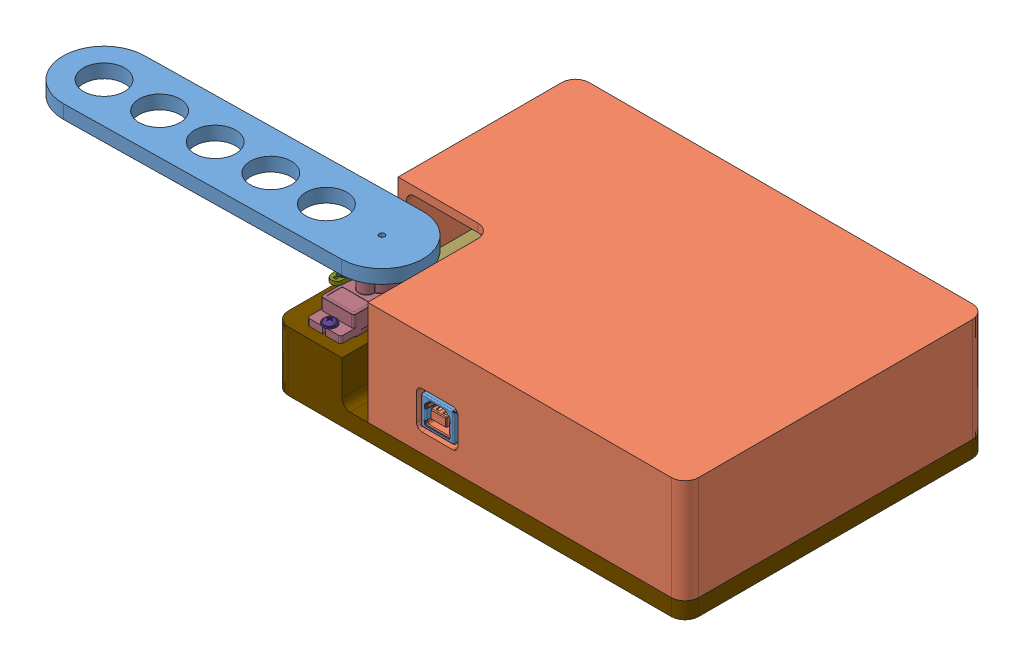
SolidWorks assembly mounted_assem, configuration Default. Lengths in mm.
Overall size (251.12 44 110).
146 component instances, 56 part files, 53 mates.
Components (placement in the parent):
- arduino uno-1: arduino uno [Default] at (97.5 14.03 -6.35) size (53.34 15.25 74.93)
  - USB type b-1: USB type b [Default] at (-38.02 0.43 6.35) size (13.72 15.2 16.5)
    - USB SHELL-1: USB SHELL [Default] at origin size (13.72 15.2 16.5)
    - USB core-1: USB core [Default] at origin size (11.3 10.68 15.75)
    - usb top contact-1: usb top contact [Default] at (1.25 6.09 -0.38) size (1 9.67 13.76)
    - usb top contact-2: usb top contact [Default] at (-1.25 6.09 -0.38) size (1 9.67 13.76)
    - usb btm contact-1: usb btm contact [Default] at (1.25 4.41 -0.38) size (1 6.84 11.76)
    - usb btm contact-2: usb btm contact [Default] at (-1.25 4.41 -0.38) size (1 6.84 11.76)
  - dip28-1: dip28 [Default] at (-16.383 1.5 -46.355) x (0 0 -1) z (1 0 0) size (35.48 7.37 10.1)
    - dip28-1: dip28 [Default] at origin size (35.48 2.8 10.1)
    - dip socket pin-1: dip socket pin [Default] at (-6.35 2.8 -3.81) size (1.7 7.37 1.7)
    - dip socket pin-2: dip socket pin [Default] at (1.27 2.8 -3.81) size (1.7 7.37 1.7)
    - dip socket pin-3: dip socket pin [Default] at (-16.51 2.8 3.81) size (1.7 7.37 1.7)
    - dip socket pin-4: dip socket pin [Default] at (1.27 2.8 3.81) size (1.7 7.37 1.7)
    - dip socket pin-5: dip socket pin [Default] at (6.35 2.8 -3.81) size (1.7 7.37 1.7)
    - dip socket pin-6: dip socket pin [Default] at (13.97 2.8 -3.81) size (1.7 7.37 1.7)
    - dip socket pin-7: dip socket pin [Default] at (3.81 2.8 -3.81) size (1.7 7.37 1.7)
    - dip socket pin-8: dip socket pin [Default] at (-13.97 2.8 3.81) size (1.7 7.37 1.7)
    - dip socket pin-9: dip socket pin [Default] at (16.51 2.8 3.81) size (1.7 7.37 1.7)
    - dip socket pin-10: dip socket pin [Default] at (13.97 2.8 3.81) size (1.7 7.37 1.7)
    - dip socket pin-11: dip socket pin [Default] at (-1.27 2.8 3.81) size (1.7 7.37 1.7)
    - dip socket pin-12: dip socket pin [Default] at (-11.43 2.8 -3.81) size (1.7 7.37 1.7)
    - dip socket pin-13: dip socket pin [Default] at (11.43 2.8 3.81) size (1.7 7.37 1.7)
    - dip socket pin-14: dip socket pin [Default] at (-8.89 2.8 -3.81) size (1.7 7.37 1.7)
    - dip socket pin-15: dip socket pin [Default] at (-1.27 2.8 -3.81) size (1.7 7.37 1.7)
    - dip socket pin-16: dip socket pin [Default] at (16.51 2.8 -3.81) size (1.7 7.37 1.7)
    - dip socket pin-17: dip socket pin [Default] at (-13.97 2.8 -3.81) size (1.7 7.37 1.7)
    - dip socket pin-18: dip socket pin [Default] at (-3.81 2.8 3.81) size (1.7 7.37 1.7)
    - dip socket pin-19: dip socket pin [Default] at (8.89 2.8 -3.81) size (1.7 7.37 1.7)
    - dip socket pin-20: dip socket pin [Default] at (-6.35 2.8 3.81) size (1.7 7.37 1.7)
    - dip socket pin-21: dip socket pin [Default] at (3.81 2.8 3.81) size (1.7 7.37 1.7)
    - dip socket pin-22: dip socket pin [Default] at (11.43 2.8 -3.81) size (1.7 7.37 1.7)
    - dip socket pin-23: dip socket pin [Default] at (8.89 2.8 3.81) size (1.7 7.37 1.7)
    - dip socket pin-24: dip socket pin [Default] at (-16.51 2.8 -3.81) size (1.7 7.37 1.7)
    - dip socket pin-25: dip socket pin [Default] at (-3.81 2.8 -3.81) size (1.7 7.37 1.7)
    - dip socket pin-26: dip socket pin [Default] at (-8.89 2.8 3.81) size (1.7 7.37 1.7)
    - dip socket pin-27: dip socket pin [Default] at (-11.43 2.8 3.81) size (1.7 7.37 1.7)
    - dip socket pin-28: dip socket pin [Default] at (6.35 2.8 3.81) size (1.7 7.37 1.7)
  - RESET BUTTON-1: RESET BUTTON [Default] at (-49.403 0 -6.35) size (6.2 3.1 9.6)
    - RESET CORE-1: RESET CORE [Default] at (0 0.1 0) x (-1 0 0) z (0 0 -1) size (6.2 3.1 9.6)
    - RESET-1: RESET [Default] at (0 0.1 0) x (0 0 1) z (-1 0 0) size (7.3 2 6.2)
  - unoboard blue-1: unoboard blue [Default] at origin size (53.34 1.65 68.58)
  - 47uf CAP Dcase-1: 47uf CAP Dcase [Default] at (-9.4141 0 -25.7132) x (0 0 -1) z (1 0 0) size (6.6 5.81 8)
  - 47uf CAP Dcase-2: 47uf CAP Dcase [Default] at (-9.4141 0 -18.4991) x (0 0 -1) z (1 0 0) size (6.6 5.81 8)
  - power jack-1: power jack [Default] at (-7.675 0 1.905) size (11.2 15.2 15.9)
  - crystal-1: crystal [Default] at (-26.162 0 -18.923) x (1 0 0) z (0 0 -1) size (4 5 11)
  - 2pin_header__02-1: 2pin_header__02 [Default] at (-46.23 0 -20.83) size (5 11.75 2.54)
  - 2pin_header__02-2: 2pin_header__02 [Default] at (-27.89 0 -64.91) x (0 0 1) z (-1 0 0) size (5 11.75 2.54)
  - 2pin_header__02-3: 2pin_header__02 [Default] at (-46.23 0 -15.75) size (5 11.75 2.54)
  - 2pin_header__02-4: 2pin_header__02 [Default] at (-46.23 0 -18.29) size (5 11.75 2.54)
  - 2pin_header__02-5: 2pin_header__02 [Default] at (-25.35 0 -64.91) x (0 0 1) z (-1 0 0) size (5 11.75 2.54)
  - 2pin_header__02-6: 2pin_header__02 [Default] at (-30.43 0 -64.91) x (0 0 1) z (-1 0 0) size (5 11.75 2.54)
  - nano - reg-1: nano - reg [Default] at (-17.399 0 -7.747) size (6.5 1.69 8.3)
  - led-1: led [Default] at (-36.576 0 -58.42) x (0 0 1) z (-1 0 0) size (4 0.86 1.35)
  - led-2: led [Default] at (-34.29 0 -27.94) x (0 0 1) z (-1 0 0) size (4 0.86 1.35)
  - led-3: led [Default] at (-36.83 0 -27.94) x (0 0 1) z (-1 0 0) size (4 0.86 1.35)
  - led-4: led [Default] at (-42.037 0 -27.94) x (0 0 1) z (-1 0 0) size (4 0.86 1.35)
  - atmega16u2-1: atmega16u2 [Default] at (-34.671 0.06 -20) x (1 0 0) z (0 0 -1) size (5.5 1.01 5.5)
  - 8 PORT HEADER-1: 8 PORT HEADER [Default] at (-50.8 0 -45.72) x (0 0 -1) z (1 0 0) size (20.32 10.51 2.41)
  - 8 PORT HEADER-2: 8 PORT HEADER [Default] at (-2.54 0 -27.94) x (0 0 -1) z (1 0 0) size (20.32 10.51 2.41)
  - 6 PORT HEADER-1: 6 PORT HEADER [Default] at (-2.54 0 -50.8) x (0 0 -1) z (1 0 0) size (15.24 10.51 2.41)
  - 10 PORT HEADER-1: 10 PORT HEADER [Default] at (-50.8 0 -18.796) x (0 0 -1) z (1 0 0) size (25.4 10.51 2.41)
  - ATMEL328P-1: ATMEL328P [Default] at (-16.383 4.3 -46.355) x (0 0 -1) z (1 0 0) size (35 7.27 7.87)
  - 102 RESISTOR PACK-1: 102 RESISTOR PACK [Default] at (-39.37 0 -27.94) size (3.2 0.46 3)
  - 102 RESISTOR PACK-2: 102 RESISTOR PACK [Default] at (-33.782 0 -58.42) size (3.2 0.46 3)
  - 103 RESISTOR PACK-1: 103 RESISTOR PACK [Default] at (-23.876 0 -27.94) size (3.2 0.46 3)
  - 220 RESISTOR PACK-1: 220 RESISTOR PACK [Default] at (-36.83 0 -12.827) size (3.2 0.46 3)
  - 16mhz crystal - measured-1: 16mhz crystal - measured [Default] at (-24.892 0 -41.275) x (0 0 -1) z (1 0 0) size (3.4 0.8 2)
  - PADS001-1: PADS001 [Default] at (-39.878 0.1 -18.288) x (-1 0 0) z (0 0 1) size (4.54 0.1 4.54)
  - 603 cap on pad-1: 603 cap on pad [Default] at (-29.591 0 -22.352) x (0 0 1) z (-1 0 0) size (2.76 0.9 1.12)
  - 603 cap on pad-2: 603 cap on pad [Default] at (-29.845 0 -27.94) x (0 0 -1) z (1 0 0) size (2.76 0.9 1.12)
  - 603 cap on pad-3: 603 cap on pad [Default] at (-29.845 0 -12.065) x (0 0 1) z (-1 0 0) size (2.76 0.9 1.12)
  - 603 cap on pad-4: 603 cap on pad [Default] at (-44.45 0 -27.94) x (0 0 -1) z (1 0 0) size (2.76 0.9 1.12)
  - 603 cap on pad-5: 603 cap on pad [Default] at (-41.91 0 -12.7) x (0 0 1) z (-1 0 0) size (2.76 0.9 1.12)
  - 603 cap on pad-6: 603 cap on pad [Default] at (-29.591 0 -16.002) x (0 0 1) z (-1 0 0) size (2.76 0.9 1.12)
  - 603 cap on pad-7: 603 cap on pad [Default] at (-31.496 0 -27.94) x (0 0 -1) z (1 0 0) size (2.76 0.9 1.12)
  - 603 cap on pad-8: 603 cap on pad [Default] at (-15.24 0 -18.415) size (2.76 0.9 1.12)
  - 603 cap on pad-9: 603 cap on pad [Default] at (-15.24 0 -25.625) size (2.76 0.9 1.12)
  - ssot3-1: ssot3 [Default] at (-26.5 0 -8.128) x (-1 0 0) z (0 0 -1) size (3 1.13 3.09)
  - mf-msmf050-2-1: mf-msmf050-2 [Default] at (-26.5 0 -4.064) size (5.77 1.02 3.72)
  - lmv358-1: lmv358 [Default] at (-15.24 0 -21.971) x (0 0 -1) z (1 0 0) size (3.7 1.4 2.9)
  - lp2985dgkr-1: lp2985dgkr [Default] at (-20.32 0 -19.05) x (0 0 -1) z (1 0 0) size (5.85 1.1 3)
  - cd1206 diode-1: cd1206 diode [Default] at (-27.94 0 -59.436) x (0 0 -1) z (1 0 0) size (2.07 0.96 5)
  - cd1206 diode-2: cd1206 diode [Default] at (-46.228 0 -13.081) x (0 0 1) z (-1 0 0) size (2.07 0.96 5)
  - 603 resistor-1: 603 resistor [Default] at (-29.591 0 -19.05) x (0 0 1) z (-1 0 0) size (2.36 0.61 1.03)
  - blm21-1: blm21 [Default] at (-45.085 0 -7.62) x (0 0 -1) z (1 0 0) size (2.76 0.95 1.32)
  - m7 diode-1: m7 diode [Default] at (-2.794 0 -21.59) x (0 0 -1) z (1 0 0) size (6.66 2.35 2.5)
  - MLC0603-1: MLC0603 [Default] at (-33.655 0 -12.827) x (0 0 -1) z (1 0 0) size (2.36 0.6 1.03)
  - MLC0603-2: MLC0603 [Default] at (-39.37 0 -12.827) x (0 0 -1) z (1 0 0) size (2.36 0.6 1.03)
- mounting_plate-1: mounting_plate [FDM] at origin size (150 39 110)
- standoff-1: standoff [6mm] at (89.88 6.38 -72.39) x (0 0 1) z (-1 0 0) size (5.2 6 5.2)
- standoff-2: standoff [6mm] at (61.94 6.38 -72.39) x (0 0 1) z (-1 0 0) size (5.2 6 5.2)
- standoff-3: standoff [6mm] at (94.96 6.38 -20.32) x (0 0 1) z (-1 0 0) size (5.2 6 5.2)
- standoff-4: standoff [6mm] at (46.7 6.38 -21.59) x (0 0 1) z (-1 0 0) size (5.2 6 5.2)
- protoboard-1: protoboard [Default] at (44.16 12.38 -82) size (47.5 3 24)
- RFID.STEP-1: RFID.STEP [Default] at (117.8439 -27.45 -59.2288) x (1 0 0) z (0 1 0) size (40 60 11.55)
  - Part1^RFID.STEP-1: Part1^RFID.STEP [Default] at (-16.3439 30.7712 59.45) size (40 60 2) (virtual)
  - Part10^RFID.STEP-1: Part10^RFID.STEP [Default] at (20.709 20.1029 60.45) x (0 1 0) z (0 0 1) size (10.67 3.05 5.63) (virtual)
  - User Library-S-PWSON-N12^RFID.STEP-1: User Library-S-PWSON-N12^RFID.STEP [Default] at (4.1233 20.047 60.45) x (1 0 0) z (0 -1 0) size (3 0.8 3) (virtual)
  - User Library-Header_Male_8Pin^RFID.STEP-1: User Library-Header_Male_8Pin^RFID.STEP [Default] at (12.9823 28.5305 62.74) x (-1 0 0) z (0 0 -1) size (20.33 2.5 11.55) (virtual)
  - User Library-SMD Ceramic Capacitors_0603 (1608)_CH.STEP-1: User Library-SMD Ceramic Capacitors_0603 (1608)_CH.STEP [Default] at (-3.9959 5.9247 60.9127) size (1.68 0.88 0.93)
  - User Library-SMD Ceramic Capacitors_0603 (1608)_CH.STEP-2: User Library-SMD Ceramic Capacitors_0603 (1608)_CH.STEP [Default] at (-1.0806 5.9034 60.9127) size (1.68 0.88 0.93)
  - User Library-SMD Ceramic Capacitors_0603 (1608)_CH.STEP-3: User Library-SMD Ceramic Capacitors_0603 (1608)_CH.STEP [Default] at (2.2282 5.9089 60.9127) size (1.68 0.88 0.93)
  - User Library-SMD Ceramic Capacitors_0603 (1608)_CH.STEP-4: User Library-SMD Ceramic Capacitors_0603 (1608)_CH.STEP [Default] at (5.214 5.921 60.9127) size (1.68 0.88 0.93)
  - User Library-SMD Ceramic Capacitors_0603 (1608)_CH.STEP-5: User Library-SMD Ceramic Capacitors_0603 (1608)_CH.STEP [Default] at (8.193 5.9188 60.9127) size (1.68 0.88 0.93)
  - User Library-SMD Ceramic Capacitors_0603 (1608)_CH.STEP-6: User Library-SMD Ceramic Capacitors_0603 (1608)_CH.STEP [Default] at (11.3855 5.9271 60.9127) size (1.68 0.88 0.93)
  - User Library-SMD Ceramic Capacitors_0603 (1608)_CH.STEP-7: User Library-SMD Ceramic Capacitors_0603 (1608)_CH.STEP [Default] at (16.3593 23.3789 60.9127) size (1.68 0.88 0.93)
  - User Library-SMD Ceramic Capacitors_0603 (1608)_CH.STEP-8: User Library-SMD Ceramic Capacitors_0603 (1608)_CH.STEP [Default] at (16.3593 21.3117 60.9127) size (1.68 0.88 0.93)
  - User Library-SMD Ceramic Capacitors_0603 (1608)_CH.STEP-9: User Library-SMD Ceramic Capacitors_0603 (1608)_CH.STEP [Default] at (13.4136 25.6528 60.9127) size (1.68 0.88 0.93)
  - User Library-SMD Ceramic Capacitors_0603 (1608)_CH.STEP-10: User Library-SMD Ceramic Capacitors_0603 (1608)_CH.STEP [Default] at (13.517 19.0895 60.9127) size (1.68 0.88 0.93)
  - Part8^RFID.STEP-1: Part8^RFID.STEP [Default] at (13.517 23.4826 60.704) size (1.6 0.81 0.51) (virtual)
  - Part8^RFID.STEP-2: Part8^RFID.STEP [Default] at (13.517 21.3121 60.704) size (1.6 0.81 0.51) (virtual)
  - User Library-SMD Ceramic Capacitors_0603 (1608)_CH.STEP-11: User Library-SMD Ceramic Capacitors_0603 (1608)_CH.STEP [Default] at (-5.0547 25.4542 60.9127) size (1.68 0.88 0.93)
  - User Library-SMD Ceramic Capacitors_0603 (1608)_CH.STEP-12: User Library-SMD Ceramic Capacitors_0603 (1608)_CH.STEP [Default] at (-5.0547 21.4355 60.9127) size (1.68 0.88 0.93)
  - User Library-SMD Ceramic Capacitors_0603 (1608)_CH.STEP-13: User Library-SMD Ceramic Capacitors_0603 (1608)_CH.STEP [Default] at (-5.0547 19.367 60.9127) size (1.68 0.88 0.93)
  - Part8^RFID.STEP-3: Part8^RFID.STEP [Default] at (-5.0547 23.3861 60.704) size (1.6 0.81 0.51) (virtual)
  - Part8^RFID.STEP-4: Part8^RFID.STEP [Default] at (-10.0418 25.4159 60.704) size (1.6 0.81 0.51) (virtual)
  - Part8^RFID.STEP-5: Part8^RFID.STEP [Default] at (-10.0625 23.4569 60.704) size (1.6 0.81 0.51) (virtual)
  - Part8^RFID.STEP-6: Part8^RFID.STEP [Default] at (-10.0541 27.4204 60.704) size (1.6 0.81 0.51) (virtual)
- 94180A331_Tapered Heat-Set Inserts for Plastic-3: 94180A331_Tapered Heat-Set Inserts for Plastic [94180A331] at (49.16 4.48 -99.5) x (1 0 0) z (0 1 0) size (5.56 5.56 3.8)
- 94180A331_Tapered Heat-Set Inserts for Plastic-5: 94180A331_Tapered Heat-Set Inserts for Plastic [94180A331] at (46.7 4.48 -21.59) x (1 0 0) z (0 1 0) size (5.56 5.56 3.8)
- 94180A331_Tapered Heat-Set Inserts for Plastic-7: 94180A331_Tapered Heat-Set Inserts for Plastic [94180A331] at (61.94 4.48 -72.39) x (1 0 0) z (0 1 0) size (5.56 5.56 3.8)
- 94180A331_Tapered Heat-Set Inserts for Plastic-8: 94180A331_Tapered Heat-Set Inserts for Plastic [94180A331] at (89.88 4.48 -72.39) x (1 0 0) z (0 1 0) size (5.56 5.56 3.8)
- 94180A331_Tapered Heat-Set Inserts for Plastic-9: 94180A331_Tapered Heat-Set Inserts for Plastic [94180A331] at (94.96 4.48 -20.32) x (1 0 0) z (0 1 0) size (5.56 5.56 3.8)
- 94180A331_Tapered Heat-Set Inserts for Plastic-10: 94180A331_Tapered Heat-Set Inserts for Plastic [94180A331] at (86.66 4.48 -99.5) x (1 0 0) z (0 1 0) size (5.56 5.56 3.8)
- vl53l0x-1: vl53l0x [Default] at (6 33.27 -91) x (0 0 -1) z (0 1 0) size (25 11.3 11)
  - vl53l0x_PCB-1: vl53l0x_PCB [Default] at origin size (25 3 11)
  - pin_header-1: pin_header [Default] at (-6.5 -2.54 4) size (2.54 11.3 2.54)
  - pin_header-2: pin_header [Default] at (-3.96 -2.54 4) size (2.54 11.3 2.54)
  - pin_header-3: pin_header [Default] at (-1.42 -2.54 4) size (2.54 11.3 2.54)
  - pin_header-4: pin_header [Default] at (1.12 -2.54 4) size (2.54 11.3 2.54)
  - pin_header-5: pin_header [Default] at (3.66 -2.54 4) size (2.54 11.3 2.54)
  - pin_header-6: pin_header [Default] at (6.2 -2.54 4) size (2.54 11.3 2.54)
- door_sensor_piece-1: door_sensor_piece [Default] at (0 6 -39) x (1 0 0) z (0 1 0) size (19 33 9)
- SG90 - Micro Servo 9g - Tower Pro.STEP-1: SG90 - Micro Servo 9g - Tower Pro.STEP [Default] at (41.8832 -0.2678 -26.7233) x (0 0 1) z (-1 0 0) size (37.5 32.03 16.7)
  - SG90 - Micro Servo 9g - Tower Pro.1_Pe_a.STEP-1: SG90 - Micro Servo 9g - Tower Pro.1_Pe_a.STEP [Default] at (6.6733 16.8178 27.7832) size (32.1 29.95 12.4)
  - SG90 - Micro Servo 9g - Tower Pro.2_Pe_a^SG90 - Micro Servo 9g - Tower Pro.STEP-1: SG90 - Micro Servo 9g - Tower Pro.2_Pe_a^SG90 - Micro Servo 9g - Tower Pro.STEP [Default] at (1.5233 37.9178 27.7832) size (19.5 3.8 6.9) (virtual)
  - SG90 - Micro Servo 9g - Tower Pro.3_Pe_a^SG90 - Micro Servo 9g - Tower Pro.STEP-1: SG90 - Micro Servo 9g - Tower Pro.3_Pe_a^SG90 - Micro Servo 9g - Tower Pro.STEP [Default] at (1.5233 37.9178 27.7832) size (32.1 3.8 6.9) (virtual)
  - SG90 - Micro Servo 9g - Tower Pro.4_Pe_a^SG90 - Micro Servo 9g - Tower Pro.STEP-1: SG90 - Micro Servo 9g - Tower Pro.4_Pe_a^SG90 - Micro Servo 9g - Tower Pro.STEP [Default] at (1.5233 37.9178 27.7832) size (34.5 3.8 16.7) (virtual)
  - SG90 - Micro Servo 9g - Tower Pro.5_BS EN ISO 7045 - M2 x 8 - Z - 8S^SG90 - Micro Servo 9g - Tower Pro.STEP-1: SG90 - Micro Servo 9g - Tower Pro.5_BS EN ISO 7045 - M2 x 8 - Z - 8S^SG90 - Micro Servo 9g - Tower Pro.STEP [Default] at (20.5733 26.0678 27.7832) x (0 -1 0) z (0 0 1) size (9.57 4.8 4.8) (virtual)
  - SG90 - Micro Servo 9g - Tower Pro.5_BS EN ISO 7045 - M2 x 8 - Z - 8S^SG90 - Micro Servo 9g - Tower Pro.STEP-2: SG90 - Micro Servo 9g - Tower Pro.5_BS EN ISO 7045 - M2 x 8 - Z - 8S^SG90 - Micro Servo 9g - Tower Pro.STEP [Default] at (-7.2267 26.0678 27.7832) x (0 -1 0) z (0 0 -1) size (9.57 4.8 4.8) (virtual)
  - SG90 - Micro Servo 9g - Tower Pro.6_BS EN ISO 7045 - M2 x 4 - Z - 4S^SG90 - Micro Servo 9g - Tower Pro.STEP-1: SG90 - Micro Servo 9g - Tower Pro.6_BS EN ISO 7045 - M2 x 4 - Z - 4S^SG90 - Micro Servo 9g - Tower Pro.STEP [Default] at (1.5233 38.2178 27.7832) x (0 -1 0) z (0 0 1) size (5.28 3.1 3.1) (virtual)
- standoff-9: standoff [6mm] at (86.66 6.38 -99.5) x (0 0 1) z (-1 0 0) size (5.2 6 5.2)
- standoff-10: standoff [6mm] at (49.16 6.38 -99.5) x (0 0 1) z (-1 0 0) size (5.2 6 5.2)
- blocker-1: blocker [Default] at (-101.1242 37.65 -38.3678) x (0.015916 0 0.999873) z (-0.999873 0 0.015916) size (30 5 130)
- lid-1: lid [Default] at (0 6 0) size (150 38 110)
Mates (geometry in assembly coordinates):
- Coincident4: coincident aligned: plane of mounting_plate-1 through (0 0 0) normal (0 0 1)
- Coincident5: coincident aligned: plane of mounting_plate-1 through (0 0 0) normal (0 1 0)
- Coincident6: coincident aligned: plane of mounting_plate-1 through (0 0 0) normal (1 0 0)
- Concentric1: concentric anti-aligned: cylinder of arduino uno-1/unoboard blue-1 through (89.88 12.38 -72.39) axis (0 1 0) radius 1.5875; cylinder of standoff-1 through (89.88 12.38 -72.39) axis (0 -1 0) radius 1.6
- Coincident9: coincident anti-aligned: plane of arduino uno-1/unoboard blue-1 through (97.5 12.38 -6.35) normal (0 -1 0); plane of standoff-1 through (89.88 12.38 -72.39) normal (0 1 0)
- Concentric2: concentric anti-aligned: cylinder of arduino uno-1/unoboard blue-1 through (61.94 12.38 -72.39) axis (0 1 0) radius 1.5875; cylinder of standoff-2 through (61.94 12.38 -72.39) axis (0 -1 0) radius 1.6
- Coincident10: coincident anti-aligned: plane of arduino uno-1/unoboard blue-1 through (97.5 12.38 -6.35) normal (0 -1 0); plane of standoff-2 through (61.94 12.38 -72.39) normal (0 1 0)
- Concentric3: concentric anti-aligned: cylinder of arduino uno-1/unoboard blue-1 through (94.96 12.38 -20.32) axis (0 1 0) radius 1.5875; cylinder of standoff-3 through (94.96 12.38 -20.32) axis (0 -1 0) radius 1.6
- Coincident11: coincident anti-aligned: plane of arduino uno-1/unoboard blue-1 through (97.5 12.38 -6.35) normal (0 -1 0); plane of standoff-3 through (94.96 12.38 -20.32) normal (0 1 0)
- Concentric4: concentric anti-aligned: cylinder of arduino uno-1/unoboard blue-1 through (46.7 12.38 -21.59) axis (0 1 0) radius 1.5875; cylinder of standoff-4 through (46.7 12.38 -21.59) axis (0 -1 0) radius 1.6
- Coincident12: coincident anti-aligned: plane of arduino uno-1/unoboard blue-1 through (97.5 12.38 -6.35) normal (0 -1 0); plane of standoff-4 through (46.7 12.38 -21.59) normal (0 1 0)
- Parallel5: parallel anti-aligned: plane of mounting_plate-1 through (0 6 0) normal (0 1 0); plane of RFID.STEP-1/Part1^RFID.STEP-1 through (101.5 32 -90) normal (0 -1 0)
- Distance5: distance = 20 mm aligned: plane of RFID.STEP-1/Part1^RFID.STEP-1 through (101.5 33 -90) normal (0 0 -1); plane of mounting_plate-1 through (0 6 -110) normal (0 0 -1)
- Concentric11: concentric aligned: cylinder of mounting_plate-1 through (49.16 6 -99.5) axis (0 1 0) radius 1.9304; cylinder of 94180A331_Tapered Heat-Set Inserts for Plastic-3 through (49.16 6.38 -99.5) axis (0 1 0) radius 1.5
- Coincident31: coincident anti-aligned: plane of mounting_plate-1 through (0 6 0) normal (0 1 0); plane of 94180A331_Tapered Heat-Set Inserts for Plastic-3 through (49.16 6 -102.28) normal (0 -1 0)
- Concentric14: concentric aligned: cylinder of mounting_plate-1 through (86.66 6 -99.5) axis (0 1 0) radius 1.9304; cylinder of 94180A331_Tapered Heat-Set Inserts for Plastic-10 through (86.66 6.38 -99.5) axis (0 1 0) radius 1.5
- Coincident34: coincident anti-aligned: plane of mounting_plate-1 through (0 6 0) normal (0 1 0); plane of 94180A331_Tapered Heat-Set Inserts for Plastic-10 through (86.66 6 -102.28) normal (0 -1 0)
- Concentric16: concentric aligned: cylinder of mounting_plate-1 through (46.7 6 -21.59) axis (0 1 0) radius 1.9304; cylinder of 94180A331_Tapered Heat-Set Inserts for Plastic-5 through (46.7 6.38 -21.59) axis (0 1 0) radius 1.5
- Coincident36: coincident anti-aligned: plane of mounting_plate-1 through (0 6 0) normal (0 1 0); plane of 94180A331_Tapered Heat-Set Inserts for Plastic-5 through (46.7 6 -24.37) normal (0 -1 0)
- Concentric17: concentric aligned: cylinder of mounting_plate-1 through (61.94 6 -72.39) axis (0 1 0) radius 1.9304; cylinder of 94180A331_Tapered Heat-Set Inserts for Plastic-7 through (61.94 6.38 -72.39) axis (0 1 0) radius 1.5
- Coincident37: coincident anti-aligned: plane of mounting_plate-1 through (0 6 0) normal (0 1 0); plane of 94180A331_Tapered Heat-Set Inserts for Plastic-7 through (61.94 6 -75.17) normal (0 -1 0)
- Concentric18: concentric aligned: cylinder of mounting_plate-1 through (89.88 6 -72.39) axis (0 1 0) radius 1.9304; cylinder of 94180A331_Tapered Heat-Set Inserts for Plastic-8 through (89.88 6.38 -72.39) axis (0 1 0) radius 1.5
- Coincident38: coincident anti-aligned: plane of mounting_plate-1 through (0 6 0) normal (0 1 0); plane of 94180A331_Tapered Heat-Set Inserts for Plastic-8 through (89.88 6 -75.17) normal (0 -1 0)
- Concentric19: concentric aligned: cylinder of mounting_plate-1 through (94.96 6 -20.32) axis (0 1 0) radius 1.9304; cylinder of 94180A331_Tapered Heat-Set Inserts for Plastic-9 through (94.96 6.38 -20.32) axis (0 1 0) radius 1.5
- Coincident39: coincident anti-aligned: plane of mounting_plate-1 through (0 6 0) normal (0 1 0); plane of 94180A331_Tapered Heat-Set Inserts for Plastic-9 through (94.96 6 -23.1) normal (0 -1 0)
- Coincident40: coincident anti-aligned: plane of standoff-1 through (89.88 6.38 -72.39) normal (0 -1 0); plane of 94180A331_Tapered Heat-Set Inserts for Plastic-8 through (89.88 6.38 -73.89) normal (0 1 0)
- Coincident44: coincident anti-aligned: plane of mounting_plate-1 through (7 36 -106) normal (-1 0 0); plane of vl53l0x-1/vl53l0x_PCB-1 through (7 33.27 -91) normal (1 0 0)
- Coincident45: coincident anti-aligned: plane of mounting_plate-1 through (0 36 0) normal (0 1 0); plane of vl53l0x-1/pin_header-6 through (6 36 -98.17) normal (0 -1 0)
- Coincident46: coincident aligned: plane of mounting_plate-1 through (0 0 -91) normal (0 0 -1); plane of vl53l0x-1/vl53l0x_PCB-1 through (6 33.27 -91) normal (0 0 -1)
- Coincident47: coincident anti-aligned: plane of mounting_plate-1 through (0 6 0) normal (0 1 0); plane of door_sensor_piece-1 through (0 6 -39) normal (0 -1 0)
- Coincident48: coincident aligned: plane of mounting_plate-1 through (0 6 0) normal (-1 0 0); plane of door_sensor_piece-1 through (0 15 -39) normal (-1 0 0)
- Distance9: distance = 4 mm anti-aligned: plane of mounting_plate-1 through (7 36 -76) normal (0 0 1); plane of door_sensor_piece-1 through (0 15 -72) normal (0 0 -1)
- Distance10: distance = 8 mm aligned: plane of SG90 - Micro Servo 9g - Tower Pro.STEP-1/SG90 - Micro Servo 9g - Tower Pro.1_Pe_a.STEP-1 through (8 24.2 -35.25) normal (-1 0 0); plane of mounting_plate-1 through (0 6 0) normal (-1 0 0)
- Parallel6: parallel anti-aligned: plane of mounting_plate-1 through (0 6 0) normal (0 1 0); plane of SG90 - Micro Servo 9g - Tower Pro.STEP-1/SG90 - Micro Servo 9g - Tower Pro.1_Pe_a.STEP-1 through (8.85 6 -30.45) normal (0 -1 0)
- Distance11: distance = 4 mm aligned: plane of mounting_plate-1 through (0 6 0) normal (0 0 1); plane of SG90 - Micro Servo 9g - Tower Pro.STEP-1/SG90 - Micro Servo 9g - Tower Pro.1_Pe_a.STEP-1 through (8.85 24.2 -4) normal (0 0 1)
- Coincident53: coincident anti-aligned: plane of mounting_plate-1 through (0 6 0) normal (0 1 0); plane of SG90 - Micro Servo 9g - Tower Pro.STEP-1/SG90 - Micro Servo 9g - Tower Pro.1_Pe_a.STEP-1 through (8.85 6 -30.45) normal (0 -1 0)
- Parallel7: parallel aligned: plane of arduino uno-1/unoboard blue-1 through (97.5 12.38 -6.35) normal (1 0 0); plane of mounting_plate-1 through (150 6 0) normal (1 0 0)
- Coincident55: coincident aligned: plane of arduino uno-1/USB type b-1/USB SHELL-1 through (59.48 14.46 0) normal (0 0 1); plane of mounting_plate-1 through (0 6 0) normal (0 0 1)
- Distance13: distance = 8.5 mm aligned: plane of RFID.STEP-1/Part1^RFID.STEP-1 through (141.5 33 -90) normal (1 0 0); plane of mounting_plate-1 through (150 6 0) normal (1 0 0)
- Distance14: distance = 4 mm anti-aligned: plane of RFID.STEP-1/Part1^RFID.STEP-1 through (101.5 33 -90) normal (-1 0 0); plane of arduino uno-1/unoboard blue-1 through (97.5 12.38 -6.35) normal (1 0 0)
- Concentric20: concentric anti-aligned: cylinder of protoboard-1 through (86.66 15.38 -99.5) axis (0 1 0) radius 1.5; cylinder of standoff-9 through (86.66 12.38 -99.5) axis (0 -1 0) radius 1.6
- Coincident59: coincident anti-aligned: plane of protoboard-1 through (44.16 12.38 -82) normal (0 -1 0); plane of standoff-9 through (86.66 12.38 -99.5) normal (0 1 0)
- Concentric21: concentric anti-aligned: cylinder of protoboard-1 through (49.16 15.38 -99.5) axis (0 1 0) radius 1.5; cylinder of standoff-10 through (49.16 12.38 -99.5) axis (0 -1 0) radius 1.6
- Coincident60: coincident anti-aligned: plane of protoboard-1 through (44.16 12.38 -82) normal (0 -1 0); plane of standoff-10 through (49.16 12.38 -99.5) normal (0 1 0)
- Distance15: distance = 4 mm aligned: plane of protoboard-1 through (44.16 12.379 -106) normal (0 0 -1); plane of mounting_plate-1 through (0 6 -110) normal (0 0 -1)
- Coincident62: coincident aligned: plane of arduino uno-1/unoboard blue-1 through (44.16 12.38 -6.35) normal (-1 0 0); plane of protoboard-1 through (44.16 15.38 -82) normal (-1 0 0)
- Coincident63: coincident anti-aligned: plane of 94180A331_Tapered Heat-Set Inserts for Plastic-3 through (49.16 6.38 -101) normal (0 1 0); plane of standoff-10 through (49.16 6.38 -99.5) normal (0 -1 0)
- Coincident67: coincident anti-aligned: plane of SG90 - Micro Servo 9g - Tower Pro.STEP-1/SG90 - Micro Servo 9g - Tower Pro.4_Pe_a^SG90 - Micro Servo 9g - Tower Pro.STEP-1 through (14.1 37.65 -25.2) normal (0 1 0); plane of blocker-1 through (-101.1242 37.65 -38.3678) normal (0 -1 0)
- Coincident68: coincident anti-aligned: plane of mounting_plate-1 through (139 32 -74) normal (0 1 0); plane of RFID.STEP-1/Part1^RFID.STEP-1 through (101.5 32 -90) normal (0 -1 0)
- Coincident69: coincident aligned: plane of mounting_plate-1 through (0 6 0) normal (0 0 1); plane of lid-1 through (0 44 0) normal (0 0 1)
- Coincident70: coincident aligned: plane of mounting_plate-1 through (0 6 0) normal (-1 0 0); plane of lid-1 through (0 44 0) normal (-1 0 0)
- Coincident71: coincident anti-aligned: plane of mounting_plate-1 through (0 6 0) normal (0 1 0); plane of lid-1 through (0 6 0) normal (0 -1 0)
- Concentric22: concentric aligned: cylinder of SG90 - Micro Servo 9g - Tower Pro.STEP-1/SG90 - Micro Servo 9g - Tower Pro.2_Pe_a^SG90 - Micro Servo 9g - Tower Pro.STEP-1 through (14.1 37.65 -25.2) axis (0 1 0) radius 2.3; cylinder of blocker-1 through (14.1 42.65 -25.2) axis (0 1 0) radius 1
